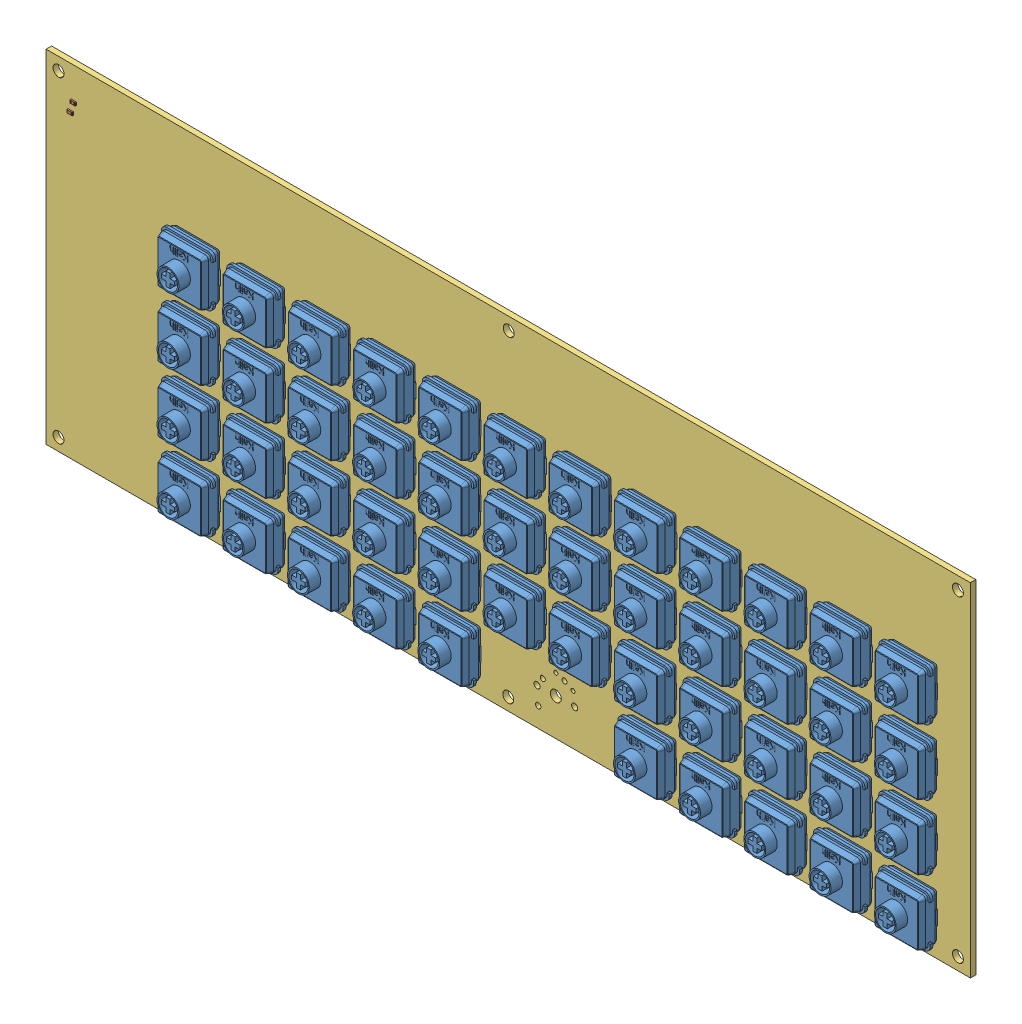
SolidWorks assembly keyboard, configuration Default. Lengths in mm.
Overall size (270 100 11.9).
97 component instances, 3 part files, 0 mates.
Components (placement in the parent):
- Kailh_PG1353-1: Kailh_PG1353 [Default] at (111.1409 -119.0307 4.15) x (0 1 0) z (1 0 0) size (15 11.9 15)
  - COMPOUND-1: COMPOUND [Default] at origin size (15 11.9 15)
- Kailh_PG1353-2: Kailh_PG1353 [Default] at (149.2409 -119.0307 4.15) x (0 1 0) z (1 0 0) size (15 11.9 15)
  - COMPOUND-1: COMPOUND [Default] at origin size (15 11.9 15)
- Kailh_PG1353-3: Kailh_PG1353 [Default] at (320.675 -176.2125 4.15) x (0 1 0) z (1 0 0) size (15 11.9 15)
  - COMPOUND-1: COMPOUND [Default] at origin size (15 11.9 15)
- Kailh_PG1353-4: Kailh_PG1353 [Default] at (263.525 -176.2125 4.15) x (0 1 0) z (1 0 0) size (15 11.9 15)
  - COMPOUND-1: COMPOUND [Default] at origin size (15 11.9 15)
- Kailh_PG1353-5: Kailh_PG1353 [Default] at (244.475 -176.2125 4.15) x (0 1 0) z (1 0 0) size (15 11.9 15)
  - COMPOUND-1: COMPOUND [Default] at origin size (15 11.9 15)
- Kailh_PG1353-6: Kailh_PG1353 [Default] at (168.275 -176.2125 4.15) x (0 1 0) z (1 0 0) size (15 11.9 15)
  - COMPOUND-1: COMPOUND [Default] at origin size (15 11.9 15)
- Kailh_PG1353-7: Kailh_PG1353 [Default] at (206.3909 -119.0307 4.15) x (0 1 0) z (1 0 0) size (15 11.9 15)
  - COMPOUND-1: COMPOUND [Default] at origin size (15 11.9 15)
- Kailh_PG1353-8: Kailh_PG1353 [Default] at (187.3409 -119.0307 4.15) x (0 1 0) z (1 0 0) size (15 11.9 15)
  - COMPOUND-1: COMPOUND [Default] at origin size (15 11.9 15)
- Kailh_PG1353-9: Kailh_PG1353 [Default] at (168.2909 -119.0307 4.15) x (0 1 0) z (1 0 0) size (15 11.9 15)
  - COMPOUND-1: COMPOUND [Default] at origin size (15 11.9 15)
- Kailh_PG1353-10: Kailh_PG1353 [Default] at (130.1909 -119.0307 4.15) x (0 1 0) z (1 0 0) size (15 11.9 15)
  - COMPOUND-1: COMPOUND [Default] at origin size (15 11.9 15)
- Kailh_PG1353-11: Kailh_PG1353 [Default] at (301.625 -176.2125 4.15) x (0 1 0) z (1 0 0) size (15 11.9 15)
  - COMPOUND-1: COMPOUND [Default] at origin size (15 11.9 15)
- Kailh_PG1353-12: Kailh_PG1353 [Default] at (282.575 -176.2125 4.15) x (0 1 0) z (1 0 0) size (15 11.9 15)
  - COMPOUND-1: COMPOUND [Default] at origin size (15 11.9 15)
- Kailh_PG1353-13: Kailh_PG1353 [Default] at (187.325 -176.2125 4.15) x (0 1 0) z (1 0 0) size (15 11.9 15)
  - COMPOUND-1: COMPOUND [Default] at origin size (15 11.9 15)
- Kailh_PG1353-14: Kailh_PG1353 [Default] at (149.225 -176.2125 4.15) x (0 1 0) z (1 0 0) size (15 11.9 15)
  - COMPOUND-1: COMPOUND [Default] at origin size (15 11.9 15)
- Kailh_PG1353-15: Kailh_PG1353 [Default] at (130.175 -176.2125 4.15) x (0 1 0) z (1 0 0) size (15 11.9 15)
  - COMPOUND-1: COMPOUND [Default] at origin size (15 11.9 15)
- Kailh_PG1353-16: Kailh_PG1353 [Default] at (111.125 -176.2125 4.15) x (0 1 0) z (1 0 0) size (15 11.9 15)
  - COMPOUND-1: COMPOUND [Default] at origin size (15 11.9 15)
- Kailh_PG1353-17: Kailh_PG1353 [Default] at (320.675 -157.1308 4.15) x (0 1 0) z (1 0 0) size (15 11.9 15)
  - COMPOUND-1: COMPOUND [Default] at origin size (15 11.9 15)
- Kailh_PG1353-18: Kailh_PG1353 [Default] at (301.625 -157.1308 4.15) x (0 1 0) z (1 0 0) size (15 11.9 15)
  - COMPOUND-1: COMPOUND [Default] at origin size (15 11.9 15)
- Kailh_PG1353-19: Kailh_PG1353 [Default] at (282.575 -157.1308 4.15) x (0 1 0) z (1 0 0) size (15 11.9 15)
  - COMPOUND-1: COMPOUND [Default] at origin size (15 11.9 15)
- Kailh_PG1353-20: Kailh_PG1353 [Default] at (263.525 -157.1308 4.15) x (0 1 0) z (1 0 0) size (15 11.9 15)
  - COMPOUND-1: COMPOUND [Default] at origin size (15 11.9 15)
- Kailh_PG1353-21: Kailh_PG1353 [Default] at (244.475 -157.1625 4.15) x (0 1 0) z (1 0 0) size (15 11.9 15)
  - COMPOUND-1: COMPOUND [Default] at origin size (15 11.9 15)
- Kailh_PG1353-22: Kailh_PG1353 [Default] at (225.425 -157.1625 4.15) x (0 1 0) z (1 0 0) size (15 11.9 15)
  - COMPOUND-1: COMPOUND [Default] at origin size (15 11.9 15)
- Kailh_PG1353-23: Kailh_PG1353 [Default] at (206.375 -157.1308 4.15) x (0 1 0) z (1 0 0) size (15 11.9 15)
  - COMPOUND-1: COMPOUND [Default] at origin size (15 11.9 15)
- Kailh_PG1353-24: Kailh_PG1353 [Default] at (187.325 -157.1625 4.15) x (0 1 0) z (1 0 0) size (15 11.9 15)
  - COMPOUND-1: COMPOUND [Default] at origin size (15 11.9 15)
- Kailh_PG1353-25: Kailh_PG1353 [Default] at (168.275 -157.1625 4.15) x (0 1 0) z (1 0 0) size (15 11.9 15)
  - COMPOUND-1: COMPOUND [Default] at origin size (15 11.9 15)
- Kailh_PG1353-26: Kailh_PG1353 [Default] at (149.225 -157.1308 4.15) x (0 1 0) z (1 0 0) size (15 11.9 15)
  - COMPOUND-1: COMPOUND [Default] at origin size (15 11.9 15)
- Kailh_PG1353-27: Kailh_PG1353 [Default] at (130.175 -157.1308 4.15) x (0 1 0) z (1 0 0) size (15 11.9 15)
  - COMPOUND-1: COMPOUND [Default] at origin size (15 11.9 15)
- Kailh_PG1353-28: Kailh_PG1353 [Default] at (111.125 -157.1308 4.15) x (0 1 0) z (1 0 0) size (15 11.9 15)
  - COMPOUND-1: COMPOUND [Default] at origin size (15 11.9 15)
- Kailh_PG1353-29: Kailh_PG1353 [Default] at (320.675 -138.1125 4.15) x (0 1 0) z (1 0 0) size (15 11.9 15)
  - COMPOUND-1: COMPOUND [Default] at origin size (15 11.9 15)
- Kailh_PG1353-30: Kailh_PG1353 [Default] at (301.625 -138.1125 4.15) x (0 1 0) z (1 0 0) size (15 11.9 15)
  - COMPOUND-1: COMPOUND [Default] at origin size (15 11.9 15)
- Kailh_PG1353-31: Kailh_PG1353 [Default] at (282.575 -138.1125 4.15) x (0 1 0) z (1 0 0) size (15 11.9 15)
  - COMPOUND-1: COMPOUND [Default] at origin size (15 11.9 15)
- Kailh_PG1353-32: Kailh_PG1353 [Default] at (263.525 -138.1125 4.15) x (0 1 0) z (1 0 0) size (15 11.9 15)
  - COMPOUND-1: COMPOUND [Default] at origin size (15 11.9 15)
- Kailh_PG1353-33: Kailh_PG1353 [Default] at (244.475 -138.1125 4.15) x (0 1 0) z (1 0 0) size (15 11.9 15)
  - COMPOUND-1: COMPOUND [Default] at origin size (15 11.9 15)
- Kailh_PG1353-34: Kailh_PG1353 [Default] at (225.425 -138.0807 4.15) x (0 1 0) z (1 0 0) size (15 11.9 15)
  - COMPOUND-1: COMPOUND [Default] at origin size (15 11.9 15)
- Kailh_PG1353-35: Kailh_PG1353 [Default] at (206.375 -138.1125 4.15) x (0 1 0) z (1 0 0) size (15 11.9 15)
  - COMPOUND-1: COMPOUND [Default] at origin size (15 11.9 15)
- Kailh_PG1353-36: Kailh_PG1353 [Default] at (187.325 -138.1125 4.15) x (0 1 0) z (1 0 0) size (15 11.9 15)
  - COMPOUND-1: COMPOUND [Default] at origin size (15 11.9 15)
- Kailh_PG1353-37: Kailh_PG1353 [Default] at (168.275 -138.1125 4.15) x (0 1 0) z (1 0 0) size (15 11.9 15)
  - COMPOUND-1: COMPOUND [Default] at origin size (15 11.9 15)
- Kailh_PG1353-38: Kailh_PG1353 [Default] at (149.225 -138.1125 4.15) x (0 1 0) z (1 0 0) size (15 11.9 15)
  - COMPOUND-1: COMPOUND [Default] at origin size (15 11.9 15)
- Kailh_PG1353-39: Kailh_PG1353 [Default] at (130.175 -138.1125 4.15) x (0 1 0) z (1 0 0) size (15 11.9 15)
  - COMPOUND-1: COMPOUND [Default] at origin size (15 11.9 15)
- Kailh_PG1353-40: Kailh_PG1353 [Default] at (111.125 -138.1125 4.15) x (0 1 0) z (1 0 0) size (15 11.9 15)
  - COMPOUND-1: COMPOUND [Default] at origin size (15 11.9 15)
- Kailh_PG1353-41: Kailh_PG1353 [Default] at (320.6909 -119.0307 4.15) x (0 1 0) z (1 0 0) size (15 11.9 15)
  - COMPOUND-1: COMPOUND [Default] at origin size (15 11.9 15)
- Kailh_PG1353-42: Kailh_PG1353 [Default] at (301.6409 -119.0307 4.15) x (0 1 0) z (1 0 0) size (15 11.9 15)
  - COMPOUND-1: COMPOUND [Default] at origin size (15 11.9 15)
- Kailh_PG1353-43: Kailh_PG1353 [Default] at (282.5909 -119.0307 4.15) x (0 1 0) z (1 0 0) size (15 11.9 15)
  - COMPOUND-1: COMPOUND [Default] at origin size (15 11.9 15)
- Kailh_PG1353-44: Kailh_PG1353 [Default] at (263.5409 -119.0307 4.15) x (0 1 0) z (1 0 0) size (15 11.9 15)
  - COMPOUND-1: COMPOUND [Default] at origin size (15 11.9 15)
- Kailh_PG1353-45: Kailh_PG1353 [Default] at (244.4909 -119.0307 4.15) x (0 1 0) z (1 0 0) size (15 11.9 15)
  - COMPOUND-1: COMPOUND [Default] at origin size (15 11.9 15)
- Kailh_PG1353-46: Kailh_PG1353 [Default] at (225.4409 -119.0307 4.15) x (0 1 0) z (1 0 0) size (15 11.9 15)
  - COMPOUND-1: COMPOUND [Default] at origin size (15 11.9 15)
- R_0603_1608Metric-1: R_0603_1608Metric [Default] at (75.184 -96.266 1.65) size (1.6 0.8 0.45)
  - SOLID-1: SOLID [Default] at origin size (1.6 0.8 0.45)
- R_0603_1608Metric-2: R_0603_1608Metric [Default] at (74.295 -99.187 1.65) x (-1 0 0) z (0 0 1) size (1.6 0.8 0.45)
  - SOLID-1: SOLID [Default] at origin size (1.6 0.8 0.45)
- COMPOUND_2-1: COMPOUND_2 [Default] at origin size (270 100 1.6)
